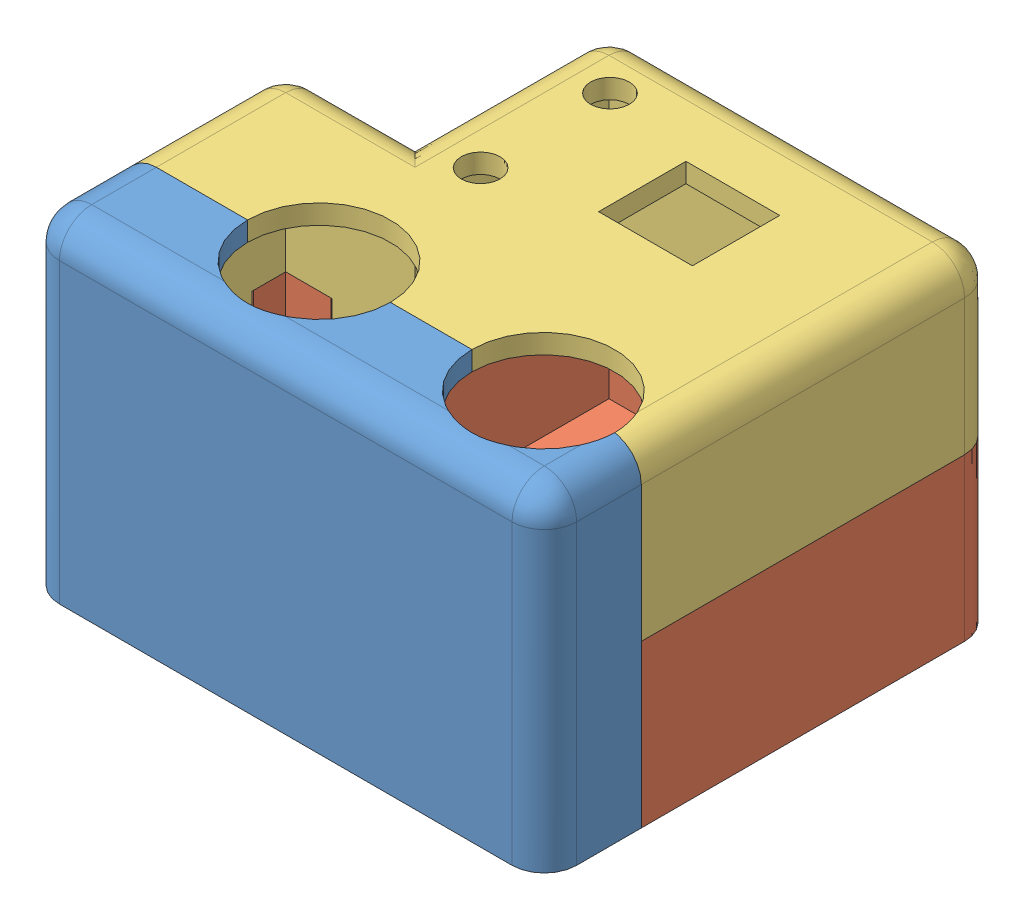
SolidWorks assembly Steckdose-House, configuration Standard. Lengths in mm.
Overall size (80 51 70).
3 component instances, 3 part files, 6 mates.
Components (placement in the parent):
- Steckdose-House-Left-1: Steckdose-House-Left [Standard] at (-45.5073 -24.1032 80) size (80 51 19.5)
- Steckdose-House-Bottom-1: Steckdose-House-Bottom [Standard] at (-45.5073 -24.1032 80) size (80 25 55)
- Steckdose-House-Top-1: Steckdose-House-Top [Standard] at (-45.5073 -24.1032 80) size (80 30.8 55)
Mates (geometry in assembly coordinates):
- Deckungsgleich4: coincident aligned: plane of Steckdose-House-Left-1 through (-45.5073 26.8968 80) normal (0 1 0); plane of Steckdose-House-Top-1 through (-45.5073 26.8968 80) normal (0 1 0)
- Deckungsgleich5: coincident aligned: plane of Steckdose-House-Left-1 through (-45.5073 -21.1032 80) normal (-1 0 0); plane of Steckdose-House-Top-1 through (-45.5073 -21.1032 80) normal (-1 0 0)
- Deckungsgleich6: coincident aligned: plane of Steckdose-House-Left-1 through (-45.5073 -21.1032 80) normal (-1 0 0); plane of Steckdose-House-Bottom-1 through (-45.5073 -21.1032 80) normal (-1 0 0)
- Deckungsgleich7: coincident aligned: plane of Steckdose-House-Left-1 through (-45.5073 -24.1032 80) normal (0 -1 0); plane of Steckdose-House-Bottom-1 through (-45.5073 -24.1032 80) normal (0 -1 0)
- Deckungsgleich8: coincident anti-aligned: plane of Steckdose-House-Left-1 through (-45.5073 -24.1032 65) normal (0 0 -1); plane of Steckdose-House-Bottom-1 through (-45.5073 -24.1032 65) normal (0 0 1)
- Deckungsgleich9: coincident anti-aligned: plane of Steckdose-House-Left-1 through (-45.5073 -24.1032 65) normal (0 0 -1); plane of Steckdose-House-Top-1 through (-45.5073 -24.1032 65) normal (0 0 1)
